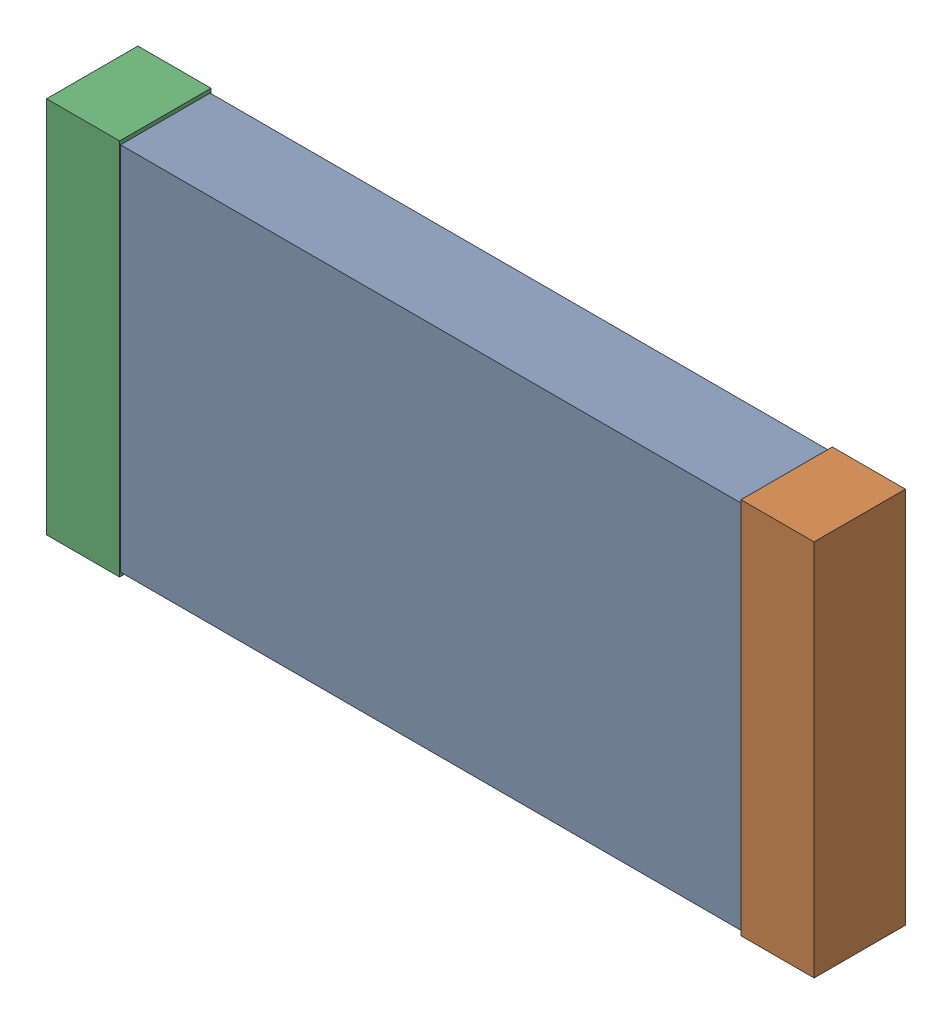
SolidWorks assembly 6132022016, configuration 默认. Lengths in mm.
Overall size (6.3 3.1 0.75).
3 component instances, 3 part files, 0 mates.
Components (placement in the parent):
- body-1-1: body-1 [默认] at (-2.55 -1.519 0.0075) size (5.1 3.04 0.73)
- term2-1: term2 [默认] at (2.55 -1.55 0) size (0.6 3.1 0.75)
- term1-1: term1 [默认] at (-3.15 -1.55 0) size (0.6 3.1 0.75)
